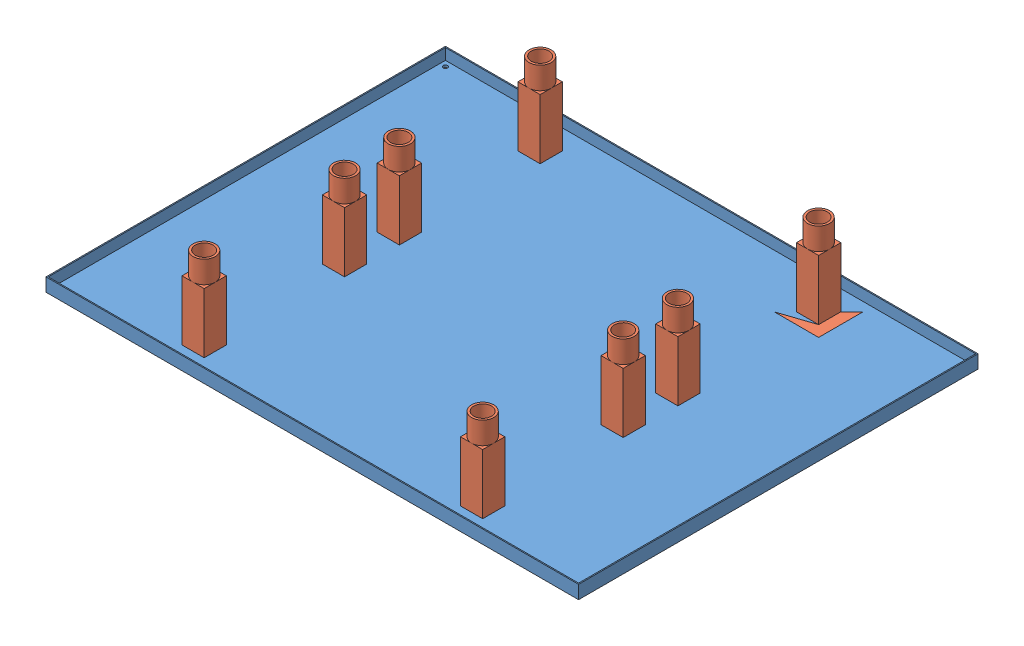
SolidWorks assembly Assem1, configuration Default. Lengths in mm.
Overall size (2960.33 380 2184.67).
9 component instances, 2 part files, 8 mates.
Components (placement in the parent):
- 1.Platform-1: 1.Platform [Default] at (-188.8966 1093.8321 2768.7727) size (2400 60 1800)
- 3.SmallJack-5: 3.SmallJack [Default] at (283.1104 1093.8321 1213.9227) size (200 380 200)
- 3.SmallJack-6: 3.SmallJack [Default] at (282.9564 1093.8321 1848.1234) size (200 380 200)
- 3.SmallJack-8: 3.SmallJack [Default] at (283.7658 1093.8321 2096.1037) size (200 380 200)
- 3.SmallJack-9: 3.SmallJack [Default] at (283.2332 1093.8321 2728.127) size (200 380 200)
- 3.SmallJack-10: 3.SmallJack [Default] at (1538.3398 1093.8321 1214.2867) size (200 380 200)
- 3.SmallJack-11: 3.SmallJack [Default] at (1538.4835 1093.8321 1848.3537) size (200 380 200)
- 3.SmallJack-12: 3.SmallJack [Default] at (1538.6825 1093.8321 2095.401) size (200 380 200)
- 3.SmallJack-13: 3.SmallJack [Default] at (1538.9308 1093.8321 2728.8572) size (200 380 200)
Mates (geometry in assembly coordinates):
- Coincident2: coincident aligned: plane of 1.Platform-1 through (-188.8966 1103.8321 2768.7727) normal (0 1 0); plane of 3.SmallJack-5 through (283.1104 1103.8321 1213.9227) normal (0 1 0)
- Coincident4: coincident: plane of 3.SmallJack-6 through (282.9564 1103.8321 1848.1234) normal (0 1 0)
- Coincident5: coincident: plane of 3.SmallJack-8 through (283.7658 1103.8321 2096.1037) normal (0 1 0)
- Coincident6: coincident: plane of 3.SmallJack-9 through (283.2332 1103.8321 2728.127) normal (0 1 0)
- Coincident7: coincident: plane of 3.SmallJack-10 through (1538.3398 1103.8321 1214.2867) normal (0 1 0)
- Coincident8: coincident: plane of 3.SmallJack-11 through (1538.4835 1103.8321 1848.3537) normal (0 1 0)
- Coincident9: coincident: plane of 3.SmallJack-12 through (1538.6825 1103.8321 2095.401) normal (0 1 0)
- Coincident10: coincident: plane of 3.SmallJack-13 through (1538.9308 1103.8321 2728.8572) normal (0 1 0)
